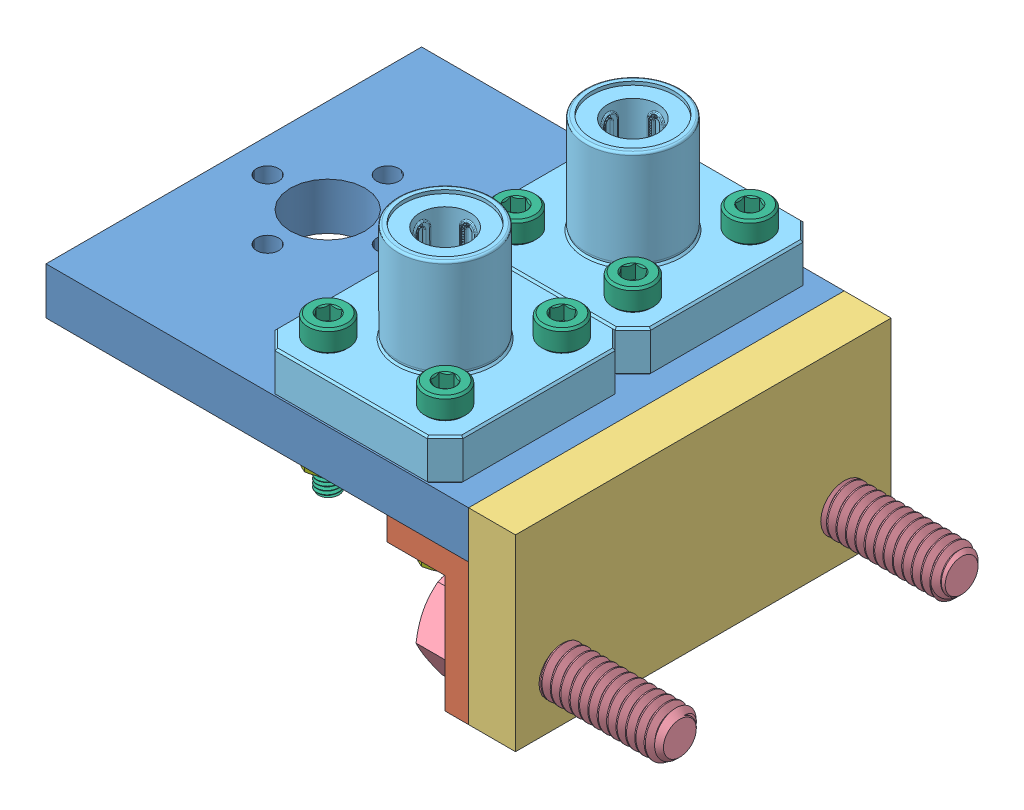
SolidWorks assembly CameraMountAssembly, configuration Default. Lengths in mm.
Overall size (79.88 46.35 52.34).
19 component instances, 7 part files, 27 mates.
Components (placement in the parent):
- bentPlateTest-1: bentPlateTest [Default] at (108.5175 46.0634 21.1584) size (58.68 6.35 50.8)
- flangeSupport-1: flangeSupport [Default] at (44.4479 39.7134 71.9584) x (0 -1 0) z (0 0 -1) size (19.05 11 50.8)
- verticalPlate-1: verticalPlate [Default] at (44.4479 20.6634 71.9584) x (0 0 -1) z (1 0 0) size (50.8 25.4 6.35)
- 92620A542_ZINC YELLOW-CHROMATE PLATED HEX HEAD SCREW-1: 92620A542_ZINC YELLOW-CHROMATE PLATED HEX HEAD SCREW [92620A542] at (51.7901 27.0134 65.6084) x (1 0 0) z (0 -0.460348 -0.887738) size (30.27 12.83 11.11)
- 92620A542_ZINC YELLOW-CHROMATE PLATED HEX HEAD SCREW-2: 92620A542_ZINC YELLOW-CHROMATE PLATED HEX HEAD SCREW [92620A542] at (51.7901 27.0134 27.5084) size (30.27 12.83 11.11)
- 6483K610_FLANGE-MOUNTED LINEAR BALL BRNG-1: 6483K610_FLANGE-MOUNTED LINEAR BALL BRNG [6483K61] at (28.5729 51.6197 33.8584) x (1 0 0) z (0 1 0) size (25.4 25.4 19.05)
- 6483K610_FLANGE-MOUNTED LINEAR BALL BRNG-2: 6483K610_FLANGE-MOUNTED LINEAR BALL BRNG [6483K61] at (28.5729 51.6197 59.2584) x (1 0 0) z (0 1 0) size (25.4 25.4 19.05)
- M3-18mmBolt-1: M3-18mmBolt [91292A029] at (36.4755 33.6197 67.161) x (0.99049 0 -0.137587) z (0 -1 0) size (5.5 5.5 21.58)
- M3-18mmBolt-2: M3-18mmBolt [91292A029] at (20.6702 33.6197 67.161) x (0.137587 0 0.99049) z (0 -1 0) size (5.5 5.5 21.58)
- M3-18mmBolt-3: M3-18mmBolt [91292A029] at (20.6702 33.6197 51.3557) x (-0.99049 0 0.137587) z (0 -1 0) size (5.5 5.5 21.58)
- M3-18mmBolt-4: M3-18mmBolt [91292A029] at (36.4755 33.6197 51.3557) x (-0.137587 0 -0.99049) z (0 -1 0) size (5.5 5.5 21.58)
- M3-18mmBolt-5: M3-18mmBolt [91292A029] at (20.6702 33.6197 41.761) x (0.995145 0 -0.098419) z (0 -1 0) size (5.5 5.5 21.58)
- M3-18mmBolt-6: M3-18mmBolt [91292A029] at (20.6702 33.6197 25.9557) x (0.098419 0 0.995145) z (0 -1 0) size (5.5 5.5 21.58)
- M3-18mmBolt-7: M3-18mmBolt [91292A029] at (36.4755 33.6197 25.9557) x (-0.995145 0 0.098419) z (0 -1 0) size (5.5 5.5 21.58)
- M3-18mmBolt-8: M3-18mmBolt [91292A029] at (36.4755 33.6197 41.761) x (-0.098419 0 -0.995145) z (0 -1 0) size (5.5 5.5 21.58)
- 90592A085_STEEL HEX NUT-1: 90592A085_STEEL HEX NUT [90592A085] at (20.6702 38.5134 25.9557) size (5.5 2.79 6.35)
- 90592A085_STEEL HEX NUT-2: 90592A085_STEEL HEX NUT [90592A085] at (20.6702 38.5134 67.161) size (5.5 2.79 6.35)
- 90592A085_STEEL HEX NUT-3: 90592A085_STEEL HEX NUT [90592A085] at (36.4755 35.3384 25.9557) size (5.5 2.79 6.35)
- 90592A085_STEEL HEX NUT-4: 90592A085_STEEL HEX NUT [90592A085] at (36.4755 35.3384 67.161) size (5.5 2.79 6.35)
Mates (geometry in assembly coordinates):
- Coincident2: coincident aligned: plane of bentPlateTest-1 through (108.5175 46.0634 71.9584) normal (0 0 1); plane of flangeSupport-1 through (44.4479 39.7134 71.9584) normal (0 0 1)
- Coincident3: coincident anti-aligned: line of bentPlateTest-1 through (44.4479 39.7134 71.9584) axis (0 0 -1); line of flangeSupport-1 through (44.4479 39.7134 21.1584) axis (0 0 1)
- Coincident4: coincident aligned: plane of bentPlateTest-1 through (-12.7021 46.0634 71.9584) normal (0 1 0); plane of verticalPlate-1 through (50.7979 46.0634 71.9584) normal (0 1 0)
- Coincident5: coincident anti-aligned: plane of bentPlateTest-1 through (44.4479 39.7134 71.9584) normal (1 0 0); plane of verticalPlate-1 through (44.4479 20.6634 71.9584) normal (-1 0 0)
- Coincident8: coincident aligned: plane of bentPlateTest-1 through (108.5175 46.0634 21.1584) normal (0 0 -1); plane of verticalPlate-1 through (50.7979 20.6634 21.1584) normal (0 0 -1)
- Coincident10: coincident anti-aligned: axis of verticalPlate-1 through (50.7979 27.0134 65.6084) axis (-1 0 0); line of 92620A542_ZINC YELLOW-CHROMATE PLATED HEX HEAD SCREW-1 through (41.2837 27.0134 65.6084) axis (1 0 0)
- Coincident11: coincident anti-aligned: plane of flangeSupport-1 through (41.2729 36.5384 21.1584) normal (-1 0 0); plane of 92620A542_ZINC YELLOW-CHROMATE PLATED HEX HEAD SCREW-1 through (41.2729 21.6078 62.1526) normal (1 0 0)
- Coincident12: coincident anti-aligned: line of verticalPlate-1 through (50.7979 27.0134 27.5084) axis (-1 0 0); line of 92620A542_ZINC YELLOW-CHROMATE PLATED HEX HEAD SCREW-2 through (41.2837 27.0134 27.5084) axis (1 0 0)
- Coincident13: coincident anti-aligned: plane of flangeSupport-1 through (41.2729 36.5384 21.1584) normal (-1 0 0); plane of 92620A542_ZINC YELLOW-CHROMATE PLATED HEX HEAD SCREW-2 through (41.2729 30.2213 33.0646) normal (1 0 0)
- Coincident14: coincident aligned: line of bentPlateTest-1 through (28.5729 39.7134 33.8584) axis (0 1 0); line of 6483K610_FLANGE-MOUNTED LINEAR BALL BRNG-1 through (28.5729 47.9004 33.8584) axis (0 1 0)
- Coincident15: coincident anti-aligned: plane of bentPlateTest-1 through (-12.7021 46.0634 71.9584) normal (0 1 0); plane of 6483K610_FLANGE-MOUNTED LINEAR BALL BRNG-1 through (15.8729 46.0634 46.5584) normal (0 -1 0)
- Coincident16: coincident aligned: line of bentPlateTest-1 through (28.5729 39.7134 59.2584) axis (0 1 0); line of 6483K610_FLANGE-MOUNTED LINEAR BALL BRNG-2 through (28.5729 47.9004 59.2584) axis (0 1 0)
- Coincident17: coincident anti-aligned: plane of bentPlateTest-1 through (-12.7021 46.0634 71.9584) normal (0 1 0); plane of 6483K610_FLANGE-MOUNTED LINEAR BALL BRNG-2 through (15.8729 46.0634 71.9584) normal (0 -1 0)
- Parallel2: parallel aligned: plane of bentPlateTest-1 through (108.5175 46.0634 71.9584) normal (0 0 1); plane of 6483K610_FLANGE-MOUNTED LINEAR BALL BRNG-2 through (18.2676 46.0634 71.9584) normal (0 0 1)
- Parallel3: parallel aligned: plane of bentPlateTest-1 through (108.5175 46.0634 21.1584) normal (0 0 -1); plane of 6483K610_FLANGE-MOUNTED LINEAR BALL BRNG-1 through (18.2676 46.0634 21.1584) normal (0 0 -1)
- Coincident22: coincident anti-aligned: plane of 6483K610_FLANGE-MOUNTED LINEAR BALL BRNG-2 through (15.8729 51.6197 71.9584) normal (0 1 0); plane of M3-18mmBolt-1 through (36.4755 51.6197 67.161) normal (0 -1 0)
- Coincident23: coincident aligned: line of 6483K610_FLANGE-MOUNTED LINEAR BALL BRNG-2 through (36.4755 49.6347 67.161) axis (0 -1 0); line of M3-18mmBolt-1 through (36.4755 51.6197 67.161) axis (0 -1 0)
- Coincident24: coincident anti-aligned: plane of 6483K610_FLANGE-MOUNTED LINEAR BALL BRNG-1 through (15.8729 51.6197 46.5584) normal (0 1 0); plane of M3-18mmBolt-5 through (20.6702 51.6197 41.761) normal (0 -1 0)
- Coincident25: coincident aligned: line of 6483K610_FLANGE-MOUNTED LINEAR BALL BRNG-1 through (20.6702 49.6347 41.761) axis (0 -1 0); line of M3-18mmBolt-5 through (20.6702 51.6197 41.761) axis (0 -1 0)
- Coincident26: coincident anti-aligned: line of M3-18mmBolt-6 through (20.6702 51.6197 25.9557) axis (0 -1 0); line of 90592A085_STEEL HEX NUT-1 through (20.6702 38.887 25.9557) axis (0 1 0)
- Coincident27: coincident anti-aligned: plane of bentPlateTest-1 through (44.4479 39.7134 71.9584) normal (0 -1 0); plane of 90592A085_STEEL HEX NUT-1 through (17.9202 39.7134 24.368) normal (0 1 0)
- Coincident28: coincident aligned: line of M3-18mmBolt-2 through (20.6702 51.6197 67.161) axis (0 -1 0); line of 90592A085_STEEL HEX NUT-2 through (20.6702 39.7134 67.161) axis (0 -1 0)
- Coincident29: coincident anti-aligned: plane of bentPlateTest-1 through (44.4479 39.7134 71.9584) normal (0 -1 0); plane of 90592A085_STEEL HEX NUT-2 through (17.9202 39.7134 65.5733) normal (0 1 0)
- Coincident30: coincident anti-aligned: plane of flangeSupport-1 through (33.4479 36.5384 21.1584) normal (0 -1 0); plane of 90592A085_STEEL HEX NUT-3 through (33.7255 36.5384 24.368) normal (0 1 0)
- Coincident31: coincident aligned: line of M3-18mmBolt-7 through (36.4755 51.6197 25.9557) axis (0 -1 0); line of 90592A085_STEEL HEX NUT-3 through (36.4755 36.5384 25.9557) axis (0 -1 0)
- Coincident32: coincident aligned: line of M3-18mmBolt-1 through (36.4755 51.6197 67.161) axis (0 -1 0); line of 90592A085_STEEL HEX NUT-4 through (36.4755 36.5384 67.161) axis (0 -1 0)
- Coincident33: coincident anti-aligned: plane of flangeSupport-1 through (33.4479 36.5384 21.1584) normal (0 -1 0); plane of 90592A085_STEEL HEX NUT-4 through (33.7255 36.5384 65.5733) normal (0 1 0)
